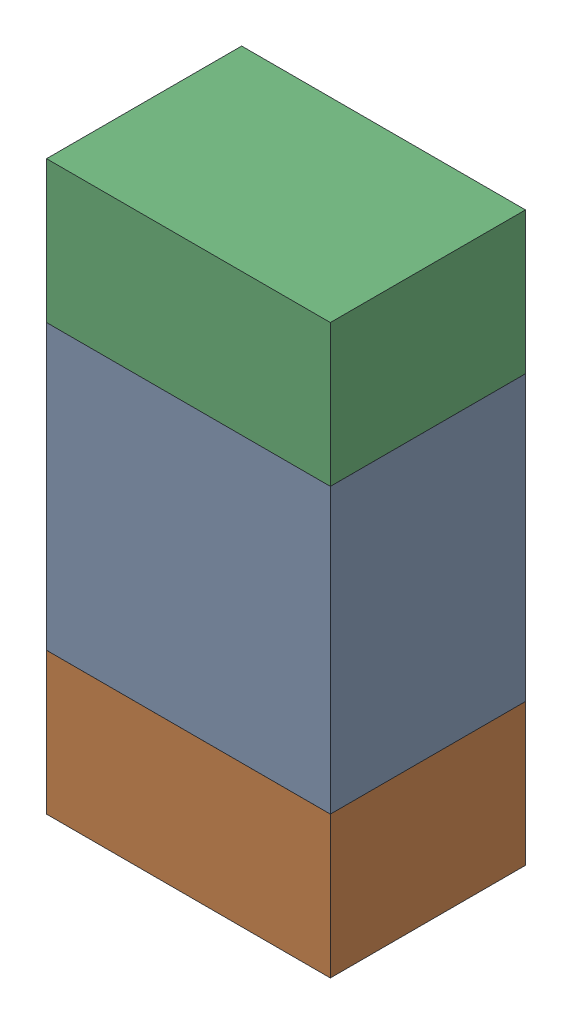
SolidWorks assembly R54, configuration ﾃﾞﾌｫﾙﾄ. Lengths in mm.
Overall size (0.8 1.6 0.55).
6 component instances, 2 part files, 0 mates.
Components (placement in the parent):
- 689261648-1: 689261648 [ﾃﾞﾌｫﾙﾄ] at (74.7499 35.75 -1.7503) size (0.8 0.8 0.55)
  - Extruded_33-1: Extruded_33 [ﾃﾞﾌｫﾙﾄ] at origin size (0.8 0.8 0.55)
- 689261784-1: 689261784 [ﾃﾞﾌｫﾙﾄ] at (74.7499 35.1499 -1.7503) size (0.8 0.4 0.55)
  - Extruded_34-1: Extruded_34 [ﾃﾞﾌｫﾙﾄ] at origin size (0.8 0.4 0.55)
- 689261784-2: 689261784 [ﾃﾞﾌｫﾙﾄ] at (74.7499 36.3499 -1.7503) size (0.8 0.4 0.55)
  - Extruded_34-1: Extruded_34 [ﾃﾞﾌｫﾙﾄ] at origin size (0.8 0.4 0.55)
